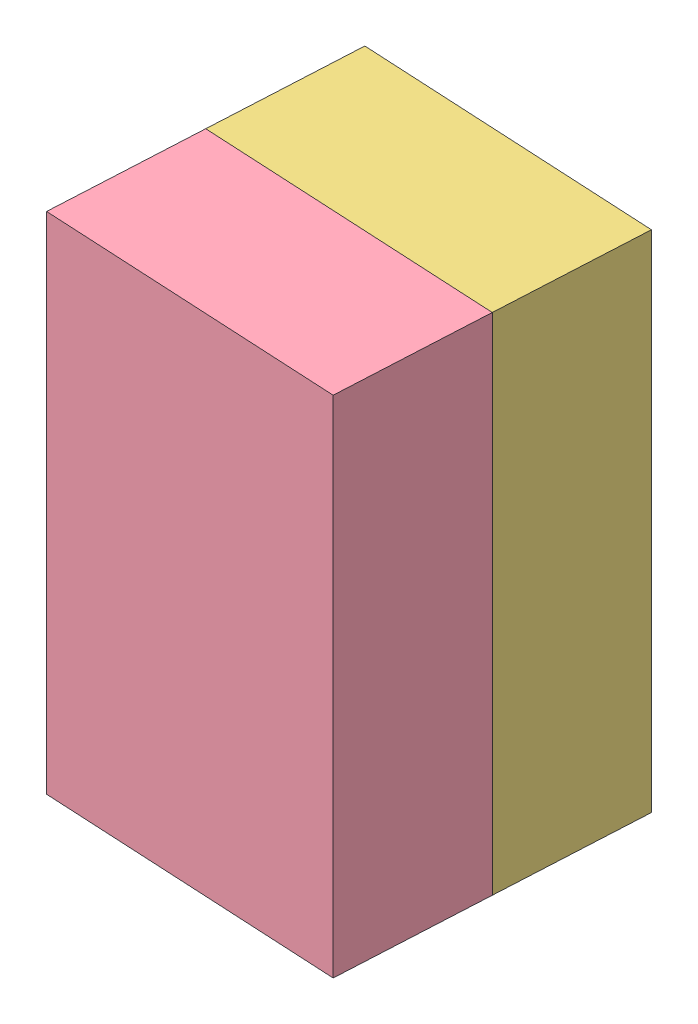
SolidWorks assembly mold assembly, configuration Default. Lengths in mm.
Overall size (157.64 250 157.64).
4 component instances, 4 part files, 8 mates.
Components (placement in the parent):
- Bottom mold-1: Bottom mold [Default] at (35.3448 20.7518 73.1547) size (80 25 80)
- Vivant bottle plain-1: Vivant bottle plain [Default] at (35.3448 20.7518 73.1547) x (-0.99863 0 -0.052325) z (0.052325 0 -0.99863) size (65.26 223.89 65.26)
- Mold1-1: Mold1 [Default] at (35.3448 20.7518 73.1547) x (-0.99863 0 -0.052325) z (0.052325 0 -0.99863) size (150 250 75)
- Mold2-1: Mold2 [Default] at (35.3448 20.7518 73.1547) x (-0.99863 0 -0.052325) z (0.052325 0 -0.99863) size (150 250 75)
Mates (geometry in assembly coordinates):
- Concentric1: concentric aligned: cylinder of Bottom mold-1 through (35.3448 7.6978 73.1547) axis (0 1 0) radius 40; cylinder of Vivant bottle plain-1 through (35.3448 244.6438 73.1547) axis (0 1 0) radius 32.63
- Coincident1: coincident aligned: circle of Bottom mold-1; circle of Vivant bottle plain-1
- Concentric2: concentric aligned: cylinder of Vivant bottle plain-1 through (35.3448 244.6438 73.1547) axis (0 1 0) radius 31.626; cylinder of Mold2-1 through (35.3448 244.6438 73.1547) axis (0 1 0) radius 31.626
- Coincident2: coincident aligned: line of Vivant bottle plain-1 through (31.3588 240.7845 84.5774) axis (0 1 0); line of Mold2-1 through (31.3588 240.7845 84.5774) axis (0 1 0)
- Coincident3: coincident aligned: circle of Vivant bottle plain-1; circle of Mold2-1
- Coincident4: coincident aligned: line of Vivant bottle plain-1 through (45.4912 239.1 66.5654) axis (0 -1 0); line of Mold1-1 through (45.4912 239.1 66.5654) axis (0 -1 0)
- Concentric3: concentric aligned: cylinder of Vivant bottle plain-1 through (35.3448 244.6438 73.1547) axis (0 1 0) radius 31.626; cylinder of Mold1-1 through (35.3448 244.6438 73.1547) axis (0 1 0) radius 31.626
- Coincident5: coincident aligned: circle of Vivant bottle plain-1; circle of Mold1-1
